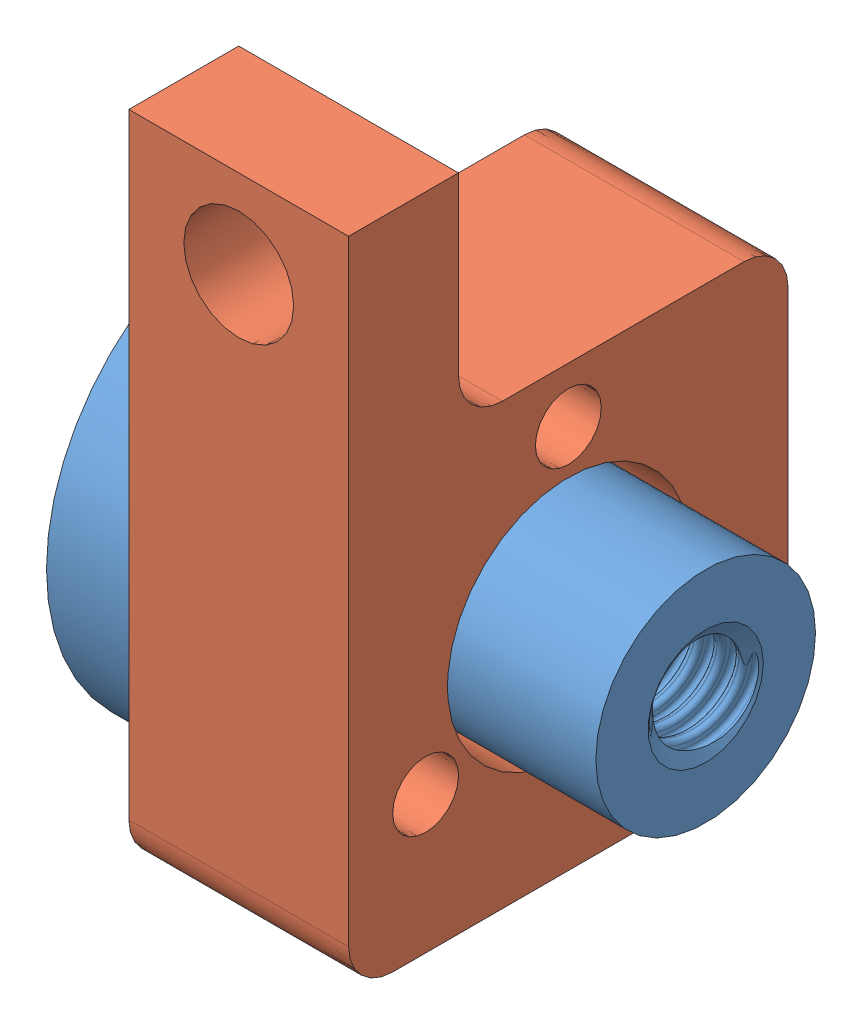
SolidWorks assembly Threaded Rod End, configuration Default. Lengths in mm.
Overall size (26.07 38.1 25.4).
2 component instances, 2 part files, 2 mates.
Components (placement in the parent):
- 6350K166_ULTRA-PRECISION LEAD SCREW-1: 6350K166_ULTRA-PRECISION LEAD SCREW [6350K166] at (-3.8393 20.2576 22.6489) size (26.07 25.4 25.4)
- LeadScrewAdapter-1: LeadScrewAdapter [Default] at (13.6232 32.9576 35.3489) x (0 1 0) z (0 0 1) size (38.1 12.7 25.4)
Mates (geometry in assembly coordinates):
- Concentric1: concentric anti-aligned: circle of 6350K166_ULTRA-PRECISION LEAD SCREW-1; circle of LeadScrewAdapter-1
- Coincident2: coincident anti-aligned: plane of 6350K166_ULTRA-PRECISION LEAD SCREW-1 through (0.9232 20.2576 22.6489) normal (1 0 0); plane of LeadScrewAdapter-1 through (0.9232 32.9576 35.3489) normal (-1 0 0)
